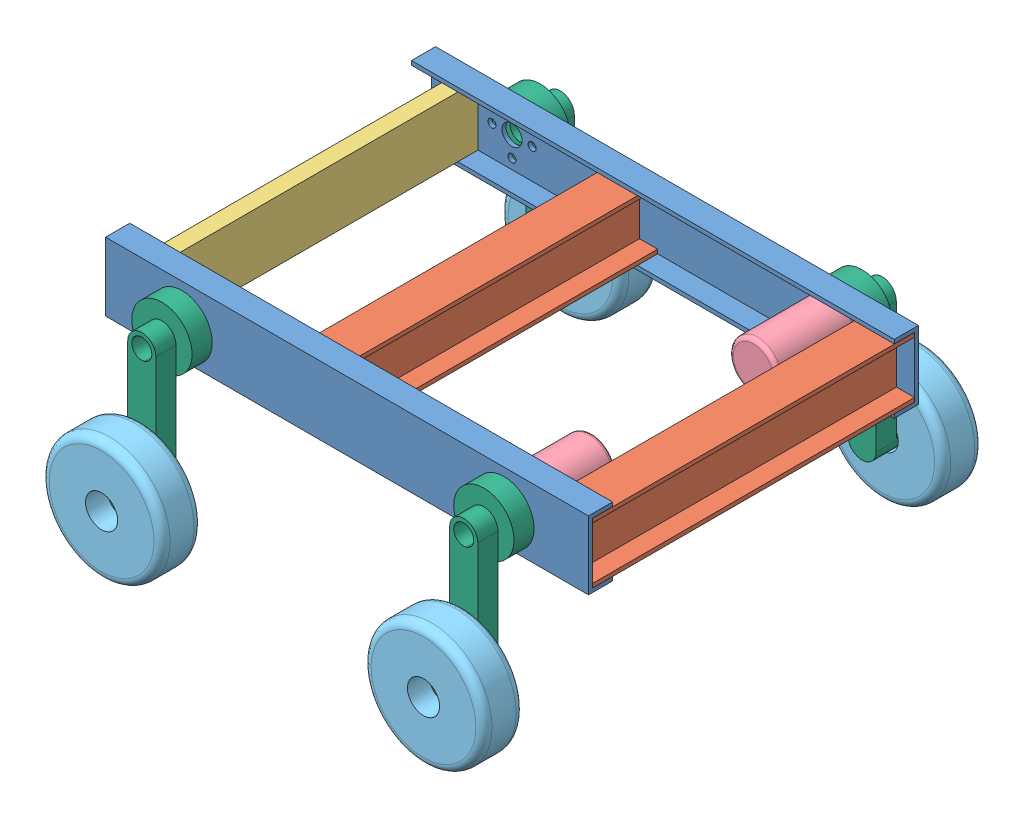
SolidWorks assembly bot1, configuration Default. Lengths in mm.
Overall size (1200.37 564.92 1240).
15 component instances, 6 part files, 35 mates.
Components (placement in the parent):
- C_section__1200-1: C_section__1200 [Default] at (-662.5218 1200 -193.637) size (1200 170 60)
- C_section__1200-2: C_section__1200 [Default] at (537.4782 1200 556.363) x (-1 0 0) z (0 0 -1) size (1200 170 60)
- I_section_800-2: I_section_800 [Default] at (487.8506 1246.7437 181.363) x (0 0 -1) z (1 0 0) size (800 150 100)
- I_section_800-3: I_section_800 [Default] at (-150.7179 1246.7437 181.363) x (0 0 -1) z (1 0 0) size (800 150 100)
- slot_slider_800-2: slot_slider_800 [Default] at (-557.1472 1200 181.363) x (-1 0 0) z (0 0 -1) size (40 150 800)
- motor_200_150_50-4: motor_200_150_50 [Default] at (337.4782 1200 581.363) x (0 0 -1) z (0.767581 -0.640952 0) size (250 120 120)
- motor_200_150_50-5: motor_200_150_50 [Default] at (337.4782 1200 -218.637) x (0 0 1) z (-0.998032 -0.062711 0) size (250 120 120)
- wheel_400_250_150-1: wheel_400_250_150 [Default] at (337.4782 900 801.363) x (0 0 -1) z (-0.22511 -0.974333 0) size (100 300 300)
- wheel_400_250_150-2: wheel_400_250_150 [Default] at (337.4782 900 -338.637) x (0 0 -1) z (-0.990145 -0.140048 0) size (100 300 300)
- link_Wheel2Chassis_300,35-1: link_Wheel2Chassis_300,35 [Default] at (337.4782 1200 601.363) x (1 0 0) z (0 -1 0) size (150 150 410)
- link_Wheel2Chassis_300,35-3: link_Wheel2Chassis_300,35 [Default] at (337.4782 1200 -238.637) x (-1 0 0) z (0 -1 0) size (150 150 410)
- link_Wheel2Chassis_300,35-4: link_Wheel2Chassis_300,35 [Default] at (-462.5218 1200 601.363) x (1 0 0) z (0 -1 0) size (150 150 410)
- link_Wheel2Chassis_300,35-5: link_Wheel2Chassis_300,35 [Default] at (-462.5218 1200 -238.637) x (-1 0 0) z (0 -1 0) size (150 150 410)
- wheel_400_250_150-3: wheel_400_250_150 [Default] at (-462.5218 900 801.363) x (0 0 -1) z (-0.22511 -0.974333 0) size (100 300 300)
- wheel_400_250_150-4: wheel_400_250_150 [Default] at (-462.4495 900.199 -338.637) x (0 0 -1) z (-0.990145 -0.140048 0) size (100 300 300)
Mates (geometry in assembly coordinates):
- Parallel1: parallel aligned: plane of C_section__1200-1 through (537.4782 1285 -168.637) normal (0 1 0); plane of C_section__1200-2 through (-662.5218 1285 531.363) normal (0 1 0)
- Parallel2: parallel anti-aligned: plane of C_section__1200-1 through (537.4782 1275 -218.637) normal (0 0 1); plane of C_section__1200-2 through (-662.5218 1275 581.363) normal (0 0 -1)
- Coincident5: coincident anti-aligned: line of I_section_800-2 through (537.8506 1275 581.363) axis (-1 0 0); line of C_section__1200-2 through (-662.5218 1275 581.363) axis (1 0 0)
- Coincident7: coincident aligned: line of C_section__1200-1 through (537.4782 1275 -218.637) axis (-1 0 0); line of I_section_800-2 through (537.8506 1275 -218.637) axis (-1 0 0)
- Parallel6: parallel aligned: plane of C_section__1200-1 through (537.4782 1285 -228.637) normal (0 0 -1); plane of I_section_800-2 through (487.8506 1246.7437 -218.637) normal (0 0 -1)
- Parallel7: parallel aligned: plane of C_section__1200-2 through (-662.5218 1285 591.363) normal (0 0 1); plane of I_section_800-2 through (487.8506 1246.7437 581.363) normal (0 0 1)
- Parallel11: parallel aligned: plane of C_section__1200-1 through (537.4782 1200 -193.637) normal (1 0 0); plane of C_section__1200-2 through (537.4782 1200 556.363) normal (1 0 0)
- Lock1: lock: unknown of C_section__1200-1; unknown of C_section__1200-2
- Parallel13: parallel anti-aligned: plane of C_section__1200-1 through (537.4782 1275 -218.637) normal (0 0 1); plane of I_section_800-3 through (-150.7179 1246.7437 -218.637) normal (0 0 -1)
- Distance2: distance = 0 mm anti-aligned: plane of C_section__1200-1 through (537.4782 1125 -168.637) normal (0 1 0); plane of I_section_800-3 through (-100.7179 1125 -218.637) normal (0 -1 0)
- Distance4: distance = 0 mm anti-aligned: plane of C_section__1200-1 through (537.4782 1275 -218.637) normal (0 0 1); plane of I_section_800-3 through (-150.7179 1246.7437 -218.637) normal (0 0 -1)
- Distance10: distance = 0 mm anti-aligned: plane of C_section__1200-1 through (537.4782 1275 -218.637) normal (0 0 1); plane of slot_slider_800-2 through (-557.1472 1200 -218.637) normal (0 0 -1)
- Distance11: distance = 0 mm anti-aligned: plane of slot_slider_800-2 through (-587.1472 1275 -218.637) normal (0 1 0); plane of C_section__1200-1 through (537.4782 1275 -168.637) normal (0 -1 0)
- Concentric2: concentric aligned: cylinder of C_section__1200-1 through (337.4782 1200 -1418.637) axis (0 0 1) radius 25; cylinder of motor_200_150_50-4 through (337.4782 1200 581.363) axis (0 0 1) radius 12.5
- Concentric5: concentric aligned: cylinder of C_section__1200-2 through (337.4782 1200 1781.363) axis (0 0 -1) radius 25; cylinder of motor_200_150_50-5 through (337.4782 1200 -218.637) axis (0 0 -1) radius 12.5
- Distance16: distance = 0 mm anti-aligned: plane of motor_200_150_50-5 through (337.4782 1200 -218.637) normal (0 0 -1); plane of C_section__1200-1 through (537.4782 1275 -218.637) normal (0 0 1)
- Distance17: distance = 0 mm anti-aligned: plane of motor_200_150_50-4 through (337.4782 1200 581.363) normal (0 0 1); plane of C_section__1200-2 through (-662.5218 1275 581.363) normal (0 0 -1)
- Concentric6: concentric anti-aligned: cylinder of motor_200_150_50-4 through (337.4782 1200 581.363) axis (0 0 1) radius 12.5; cylinder of link_Wheel2Chassis_300,35-1 through (337.4782 1200 751.363) axis (0 0 -1) radius 25
- Distance18: distance = 10 mm anti-aligned: plane of C_section__1200-2 through (-662.5218 1285 591.363) normal (0 0 1); plane of link_Wheel2Chassis_300,35-1 through (337.4782 1200 601.363) normal (0 0 -1)
- Concentric7: concentric anti-aligned: cylinder of wheel_400_250_150-1 through (337.4782 900 701.363) axis (0 0 1) radius 40; cylinder of link_Wheel2Chassis_300,35-1 through (337.4782 900 701.363) axis (0 0 -1) radius 35
- Distance20: distance = 0 mm anti-aligned: plane of link_Wheel2Chassis_300,35-1 through (337.4782 1200 701.363) normal (0 0 1); plane of wheel_400_250_150-1 through (337.4782 900 701.363) normal (0 0 -1)
- Parallel20: parallel aligned: plane of C_section__1200-2 through (537.4782 1200 556.363) normal (1 0 0); plane of link_Wheel2Chassis_300,35-1 through (372.4782 1200 701.363) normal (1 0 0)
- Concentric9: concentric anti-aligned: cylinder of motor_200_150_50-5 through (337.4782 1200 -218.637) axis (0 0 -1) radius 12.5; cylinder of link_Wheel2Chassis_300,35-3 through (337.4782 1200 -388.637) axis (0 0 1) radius 25
- Distance21: distance = 10 mm anti-aligned: plane of C_section__1200-1 through (537.4782 1285 -228.637) normal (0 0 -1); plane of link_Wheel2Chassis_300,35-3 through (337.4782 1200 -238.637) normal (0 0 1)
- Concentric12: concentric aligned: cylinder of wheel_400_250_150-2 through (337.4782 900 -438.637) axis (0 0 1) radius 40; cylinder of link_Wheel2Chassis_300,35-3 through (337.4782 900 -338.637) axis (0 0 1) radius 35
- Distance22: distance = 0 mm anti-aligned: plane of link_Wheel2Chassis_300,35-3 through (337.4782 1200 -338.637) normal (0 0 -1); plane of wheel_400_250_150-2 through (337.4782 900 -338.637) normal (0 0 1)
- Concentric14: concentric aligned: cylinder of C_section__1200-1 through (-462.5218 1200 -1418.637) axis (0 0 1) radius 25; cylinder of link_Wheel2Chassis_300,35-5 through (-462.5218 1200 -388.637) axis (0 0 1) radius 25
- Distance25: distance = 10 mm anti-aligned: plane of C_section__1200-1 through (537.4782 1285 -228.637) normal (0 0 -1); plane of link_Wheel2Chassis_300,35-5 through (-462.5218 1200 -238.637) normal (0 0 1)
- Distance26: distance = 10 mm anti-aligned: plane of C_section__1200-2 through (-662.5218 1285 591.363) normal (0 0 1); plane of link_Wheel2Chassis_300,35-4 through (-462.5218 1200 601.363) normal (0 0 -1)
- Concentric15: concentric aligned: cylinder of C_section__1200-2 through (-462.5218 1200 1781.363) axis (0 0 -1) radius 25; cylinder of link_Wheel2Chassis_300,35-4 through (-462.5218 1200 751.363) axis (0 0 -1) radius 25
- Concentric16: concentric aligned: cylinder of link_Wheel2Chassis_300,35-5 through (-462.4495 900.199 -388.637) axis (0 0 1) radius 35.2117; cylinder of wheel_400_250_150-4 through (-462.4495 900.199 -438.637) axis (0 0 1) radius 40
- Concentric17: concentric anti-aligned: cylinder of link_Wheel2Chassis_300,35-4 through (-462.5218 900 701.363) axis (0 0 -1) radius 35; cylinder of wheel_400_250_150-3 through (-462.5218 900 701.363) axis (0 0 1) radius 40
- Concentric18: concentric anti-aligned: cylinder of link_Wheel2Chassis_300,35-4 through (-462.5218 900 701.363) axis (0 0 -1) radius 35; cylinder of wheel_400_250_150-3 through (-462.5218 900 701.363) axis (0 0 1) radius 40
- Distance27: distance = 0 mm anti-aligned: plane of link_Wheel2Chassis_300,35-4 through (-462.5218 1200 701.363) normal (0 0 1); plane of wheel_400_250_150-3 through (-462.5218 900 701.363) normal (0 0 -1)
- Distance28: distance = 0 mm anti-aligned: plane of wheel_400_250_150-4 through (-462.4495 900.199 -338.637) normal (0 0 1); plane of link_Wheel2Chassis_300,35-5 through (-462.5218 1200 -338.637) normal (0 0 -1)
